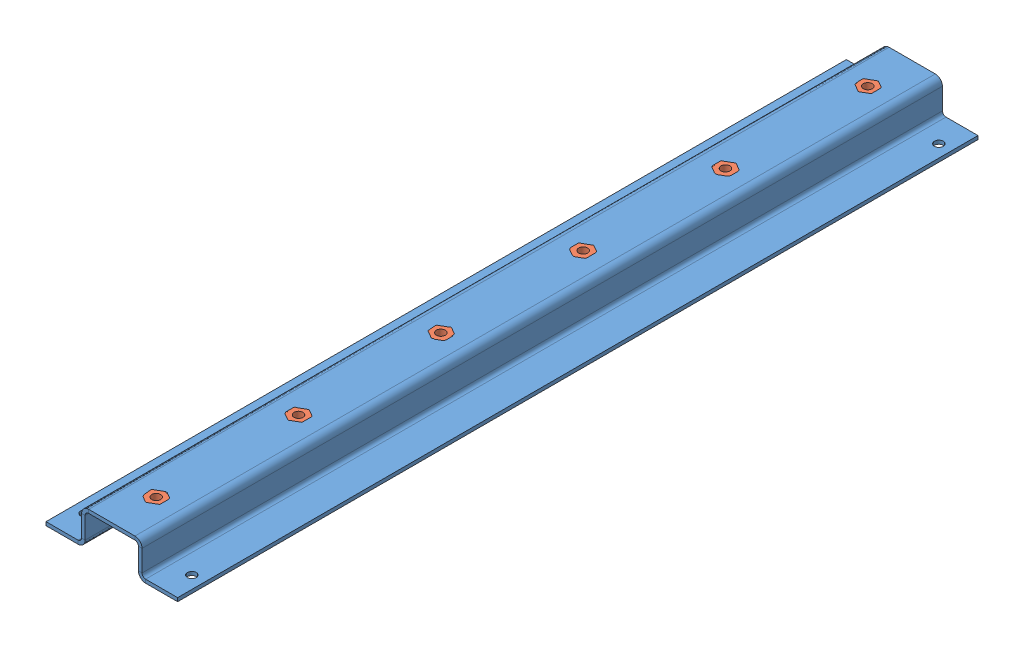
SolidWorks assembly Assemblage-ENCLOSURE-OMEGA, configuration Défaut. Lengths in mm.
Overall size (74 20 450).
7 component instances, 2 part files, 3 mates.
Components (placement in the parent):
- ENCLOSURE-OMEGA-PORTE-1: ENCLOSURE-OMEGA-PORTE [Défaut] at (-28.0104 18.296 0) size (74 20 450)
- INSERTHM6X30IN-1: INSERTHM6X30IN [Défaut] at (-28.0104 8.896 484.99) size (10 12.4 10.93)
- INSERTHM6X30IN-2: INSERTHM6X30IN [Défaut] at (-28.0104 8.896 404.98) size (10 12.4 10.93)
- INSERTHM6X30IN-3: INSERTHM6X30IN [Défaut] at (-28.0104 8.896 324.97) size (10 12.4 10.93)
- INSERTHM6X30IN-4: INSERTHM6X30IN [Défaut] at (-28.0104 8.896 244.96) size (10 12.4 10.93)
- INSERTHM6X30IN-5: INSERTHM6X30IN [Défaut] at (-28.0104 8.896 164.95) size (10 12.4 10.93)
- INSERTHM6X30IN-6: INSERTHM6X30IN [Défaut] at (-28.0104 8.896 84.94) size (10 12.4 10.93)
Mates (geometry in assembly coordinates):
- Coaxiale1: concentric anti-aligned: circle of INSERTHM6X30IN-1; circle of assembly
- Coïncidente1: coincident aligned: plane of ENCLOSURE-OMEGA-PORTE-1 through (12.4122 9.296 585) normal (0 1 0); plane of INSERTHM6X30IN-1 through (-28.0104 9.296 484.99) normal (0 1 0)
- Parallèle1: parallel aligned: line of ENCLOSURE-OMEGA-PORTE-1 through (-32.6104 9.296 482.3342) axis (0 0 1); line of INSERTHM6X30IN-1 through (-33.0104 9.296 483.2579) axis (0 0 1)
